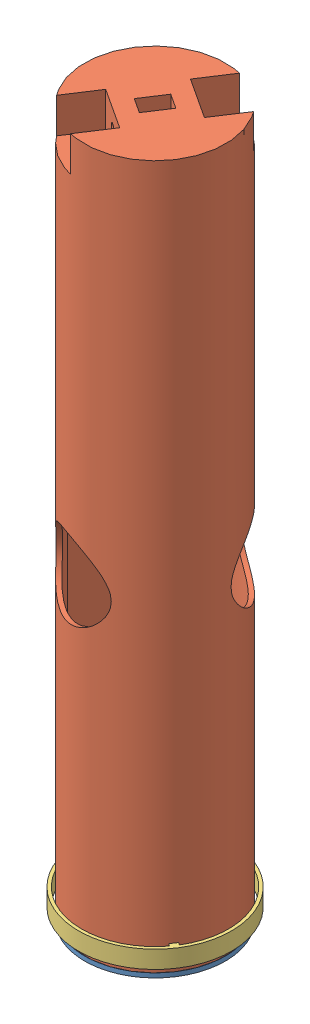
SolidWorks assembly Assem1, configuration Default. Lengths in mm.
Overall size (153.53 555.01 153.53).
3 component instances, 3 part files, 3 mates.
Components (placement in the parent):
- Glider lid-1: Glider lid [Default] at origin size (101.6 29.56 103.58)
- PayloadBay-1: PayloadBay [Default] at (0 460.375 0) x (-0.837169 0 -0.546944) z (-0.546944 0 0.837169) size (101.6 555.01 101.6)
- retaining ring-1: retaining ring [Default] at (0.015 2.1084 0.013) x (0.826256 0 0.563295) z (-0.563295 0 0.826256) size (110.49 12.7 110.49)
Mates (geometry in assembly coordinates):
- Concentric1: concentric aligned: cylinder of Glider lid-1 through (0 28.575 0) axis (0 -1 0) radius 47.625; cylinder of PayloadBay-1 through (0 460.375 0) axis (0 -1 0) radius 47.625
- Coincident1: coincident anti-aligned: plane of Glider lid-1 through (0 3.175 0) normal (0 1 0); plane of PayloadBay-1 through (0 3.175 0) normal (0 -1 0)
- Concentric2: concentric anti-aligned: cylinder of PayloadBay-1 through (0 3.175 0) axis (0 1 0) radius 50.8; cylinder of retaining ring-1 through (0 21.1584 0) axis (0 -1 0) radius 55.245
